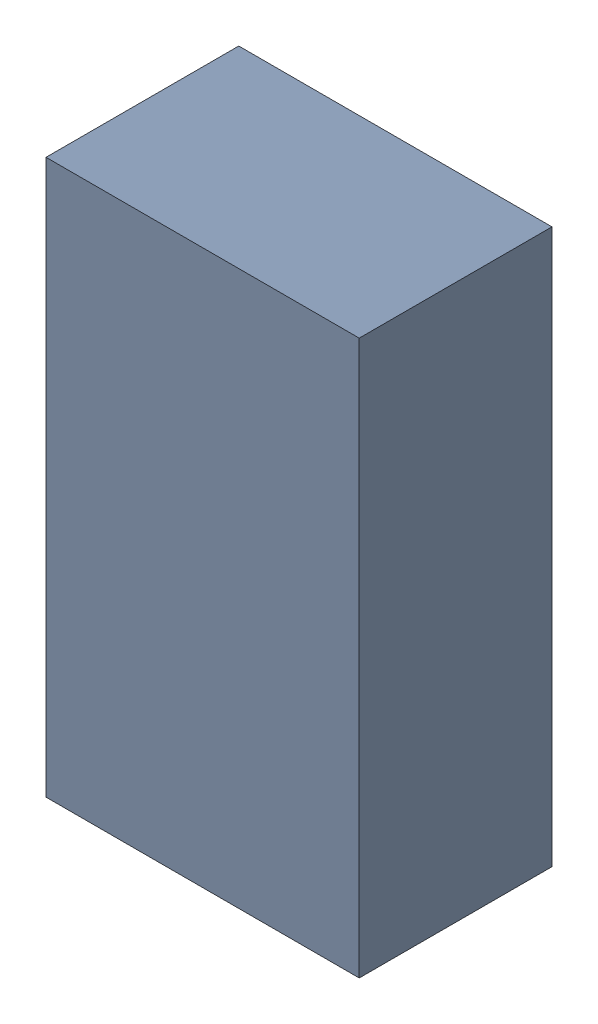
SolidWorks assembly LDO1, configuration Default. Lengths in mm.
Overall size (2.6 4.6 1.6).
2 component instances, 1 part files, 0 mates.
Components (placement in the parent):
- 1540841176-1: 1540841176 [Default] at (24.5 -12.25 0) size (2.6 4.6 1.6)
  - Extruded_2-1: Extruded_2 [Default] at origin size (2.6 4.6 1.6)
